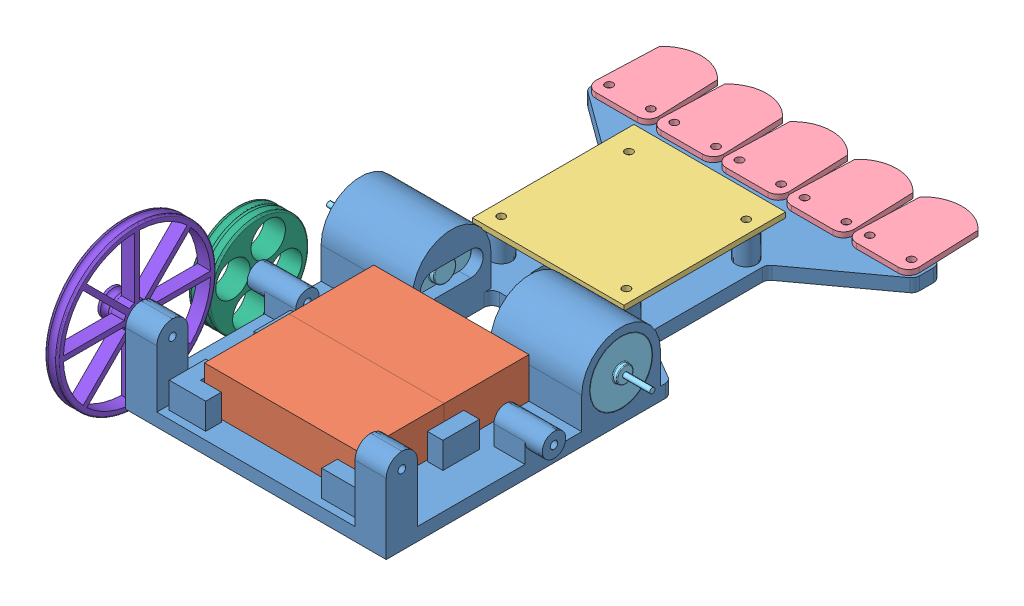
SolidWorks assembly LFR, configuration Default. Lengths in mm.
Overall size (127.6 69.01 245.09).
14 component instances, 8 part files, 39 mates.
Components (placement in the parent):
- BODY-1: BODY [Default] at origin size (126 33 200)
- BATTERY-1: BATTERY [Default] at (0 5 41.25) x (0 0 1) z (-1 0 0) size (32.5 15.5 59.5)
- BATTERY-2: BATTERY [Default] at (0 5 73.75) x (0 0 1) z (-1 0 0) size (32.5 15.5 59.5)
- MAIN-1: MAIN [Default] at (0 16 -43.1083) size (58.17 2 62)
- SENSOR-1: SENSOR [Default] at (25 5 -92.42) x (-1 0 0) z (0 0 -1) size (24 2 32.42)
- SENSOR-2: SENSOR [Default] at (-50 5 -92.42) x (-1 0 0) z (0 0 -1) size (24 2 32.42)
- SENSOR-3: SENSOR [Default] at (-25 5 -92.42) x (-1 0 0) z (0 0 -1) size (24 2 32.42)
- SENSOR-4: SENSOR [Default] at (0 5 -92.42) x (-1 0 0) z (0 0 -1) size (24 2 32.42)
- SENSOR-5: SENSOR [Default] at (50 5 -92.42) x (-1 0 0) z (0 0 -1) size (24 2 32.42)
- MM28Motor-1: MM28Motor [Default] at (-50 17.1 9.9) x (0 -0.92213 -0.386881) z (-1 0 0) size (24.2 24.2 44.5)
- MM28Motor-2: MM28Motor [Default] at (50 17.1 9.9) x (0 0.147524 -0.989058) z (1 0 0) size (24.2 24.2 44.5)
- WHEEL-1: WHEEL [Default] at (-56.6 12.5 42.2315) x (0 -0.942565 0.334022) z (-1 0 0) size (38 38 8)
- MOTOR_PULLEY-1: MOTOR_PULLEY [Default] at (-51.6 17.1 9.9) x (0 -0.289734 0.957107) z (-1 0 0) size (9 9 5)
- INTERMEDIATE-1: INTERMEDIATE [Default] at (-51.6 27 94) x (0 0 1) z (-1 0 0) size (60.5 60.5 10)
Mates (geometry in assembly coordinates):
- Coincident1: coincident anti-aligned: plane of BODY-1 through (0 5 0) normal (0 1 0); plane of BATTERY-2 through (0 5 73.75) normal (0 -1 0)
- Parallel8: parallel aligned: plane of BODY-1 through (-50 5 100) normal (0 0 1); plane of BATTERY-2 through (-29.75 20.5 90) normal (0 0 1)
- Coincident3: coincident anti-aligned: plane of BODY-1 through (0 0 0) normal (1 0 0); plane of BATTERY-2 through (0 5 73.75) normal (-1 0 0)
- Coincident4: coincident anti-aligned: plane of BATTERY-1 through (-29.75 20.5 57.5) normal (0 0 1); plane of BATTERY-2 through (-29.75 20.5 57.5) normal (0 0 -1)
- Coincident5: coincident anti-aligned: plane of BODY-1 through (0 5 0) normal (0 1 0); plane of BATTERY-1 through (0 5 41.25) normal (0 -1 0)
- Coincident6: coincident anti-aligned: plane of BODY-1 through (0 0 0) normal (1 0 0); plane of BATTERY-1 through (0 5 41.25) normal (-1 0 0)
- Coincident8: coincident aligned: plane of BODY-1 through (0 0 0) normal (1 0 0); plane of MAIN-1 through (0 16 -43.1083) normal (1 0 0)
- Coincident9: coincident anti-aligned: plane of BODY-1 through (0 5 0) normal (0 1 0); plane of SENSOR-1 through (33 5 -92.42) normal (0 -1 0)
- Coincident10: coincident anti-aligned: plane of BODY-1 through (0 5 0) normal (0 1 0); plane of SENSOR-3 through (-17 5 -92.42) normal (0 -1 0)
- Coincident11: coincident anti-aligned: plane of BODY-1 through (0 5 0) normal (0 1 0); plane of SENSOR-2 through (-42 5 -92.42) normal (0 -1 0)
- Coincident12: coincident anti-aligned: plane of BODY-1 through (0 5 0) normal (0 1 0); plane of SENSOR-5 through (58 5 -92.42) normal (0 -1 0)
- Coincident13: coincident anti-aligned: plane of BODY-1 through (0 5 0) normal (0 1 0); plane of SENSOR-4 through (8 5 -92.42) normal (0 -1 0)
- Parallel1: parallel anti-aligned: plane of BODY-1 through (-63 5 -100) normal (0 0 -1); plane of SENSOR-5 through (58 7 -88.42) normal (0 0 1)
- Parallel2: parallel anti-aligned: plane of BODY-1 through (-63 5 -100) normal (0 0 -1); plane of SENSOR-3 through (-17 7 -88.42) normal (0 0 1)
- Parallel7: parallel anti-aligned: plane of BODY-1 through (-63 5 -100) normal (0 0 -1); plane of SENSOR-2 through (-42 7 -88.42) normal (0 0 1)
- Parallel3: parallel anti-aligned: plane of BODY-1 through (-63 5 -100) normal (0 0 -1); plane of SENSOR-1 through (33 7 -88.42) normal (0 0 1)
- Parallel4: parallel anti-aligned: plane of BODY-1 through (-63 5 -100) normal (0 0 -1); plane of SENSOR-4 through (8 7 -88.42) normal (0 0 1)
- Concentric2: concentric aligned: cylinder of BODY-1 through (-19.5 17.1 9.9) axis (-1 0 0) radius 12.1; cylinder of MM28Motor-1 through (-19.5 17.1 9.9) axis (-1 0 0) radius 12.1
- Coincident23: coincident anti-aligned: plane of BODY-1 through (-19.5 0 0) normal (-1 0 0); plane of MM28Motor-1 through (-19.5 17.1 9.9) normal (1 0 0)
- Concentric3: concentric aligned: cylinder of BODY-1 through (19.5 17.1 9.9) axis (1 0 0) radius 12.1; cylinder of MM28Motor-2 through (19.5 17.1 9.9) axis (1 0 0) radius 12.1
- Coincident24: coincident anti-aligned: plane of BODY-1 through (19.5 0 0) normal (1 0 0); plane of MM28Motor-2 through (19.5 17.1 9.9) normal (-1 0 0)
- Distance2: distance = 6.6 mm anti-aligned: plane of BODY-1 through (-50 5 100) normal (-1 0 0); plane of WHEEL-1 through (-56.6 12.5 42.2315) normal (1 0 0)
- Concentric4: concentric anti-aligned: cylinder of MM28Motor-1 through (-62 17.1 9.9) axis (1 0 0) radius 1; cylinder of MOTOR_PULLEY-1 through (-51.6 17.1 9.9) axis (-1 0 0) radius 0.975
- Coincident26: coincident anti-aligned: plane of MM28Motor-1 through (-51.6 17.1 9.9) normal (-1 0 0); plane of MOTOR_PULLEY-1 through (-51.6 17.1 9.9) normal (1 0 0)
- Distance1: distance = 1.6 mm anti-aligned: plane of INTERMEDIATE-1 through (-51.6 57.25 94) normal (1 0 0); plane of BODY-1 through (-50 5 100) normal (-1 0 0)
- Concentric6: concentric aligned: cylinder of BODY-1 through (-38 12.5 42.2315) axis (-1 0 0) radius 1.45; cylinder of WHEEL-1 through (-56.6 12.5 42.2315) axis (-1 0 0) radius 1.55
- Concentric7: concentric anti-aligned: cylinder of BODY-1 through (-38 27 94) axis (-1 0 0) radius 1.45; cylinder of INTERMEDIATE-1 through (-61.6 27 94) axis (1 0 0) radius 1.55
- Coincident28: coincident anti-aligned: plane of BODY-1 through (-20.995 16 -64.1083) normal (0 1 0); plane of MAIN-1 through (0 16 -43.1083) normal (0 -1 0)
- Coincident29: coincident aligned: plane of SENSOR-2 through (-42 7 -88.42) normal (0 0 1); plane of SENSOR-3 through (-17 7 -88.42) normal (0 0 1)
- Coincident30: coincident aligned: plane of SENSOR-3 through (-17 7 -88.42) normal (0 0 1); plane of SENSOR-4 through (8 7 -88.42) normal (0 0 1)
- Coincident31: coincident aligned: plane of SENSOR-1 through (33 7 -88.42) normal (0 0 1); plane of SENSOR-4 through (8 7 -88.42) normal (0 0 1)
- Coincident32: coincident aligned: plane of SENSOR-1 through (33 7 -88.42) normal (0 0 1); plane of SENSOR-5 through (58 7 -88.42) normal (0 0 1)
- Coincident33: coincident anti-aligned: plane of BODY-1 through (0 0 0) normal (1 0 0); plane of SENSOR-4 through (0 5 -92.42) normal (-1 0 0)
- Coincident37: coincident anti-aligned: plane of BODY-1 through (-50 32.2 25) normal (0 0 1); plane of BATTERY-1 through (-29.75 20.5 25) normal (0 0 -1)
- Distance4: distance = 11.58 mm anti-aligned: plane of SENSOR-4 through (8 7 -88.42) normal (0 0 1); plane of BODY-1 through (-63 5 -100) normal (0 0 -1)
- Distance5: distance = 9 mm: cylinder of SENSOR-3 through (-17 7 -93.5) axis (0 -1 0) radius 1.5; cylinder of SENSOR-4 through (-8 7 -93.5) axis (0 -1 0) radius 1.5
- Distance6: distance = 9 mm: cylinder of SENSOR-3 through (-33 7 -93.5) axis (0 -1 0) radius 1.5; cylinder of SENSOR-2 through (-42 7 -93.5) axis (0 -1 0) radius 1.5
- Distance7: distance = 9 mm: cylinder of SENSOR-4 through (8 7 -93.5) axis (0 -1 0) radius 1.5; cylinder of SENSOR-1 through (17 7 -93.5) axis (0 -1 0) radius 1.5
- Distance8: distance = 9 mm: cylinder of SENSOR-1 through (33 7 -93.5) axis (0 -1 0) radius 1.5; cylinder of SENSOR-5 through (42 7 -93.5) axis (0 -1 0) radius 1.5
